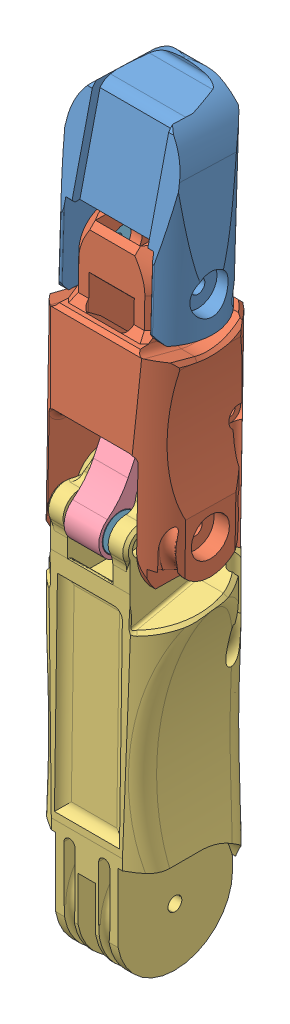
SolidWorks assembly assembly little finger, configuration Default. Lengths in mm.
Overall size (25.08 108.84 19.95).
12 component instances, 5 part files, 24 mates.
Components (placement in the parent):
- little link1-1: little link1 [Default] at (0 -2.2394 -28.6211) x (1 0 0) z (0 0.031595 0.999501) size (19.5 27.22 13.31)
- little link2-1: little link2 [Default] at (0 -32.0849 -28.1064) x (1 0 0) z (0 0.017244 0.999851) size (22.25 39.85 15.23)
- little link3-1: little link3 [Default] at (0 -80.3849 -28.1064) size (25.08 61.6 19.95)
- little linkage-1: little linkage [Default] at (0 -20.132 -28.2916) x (1 0 0) z (0 0.999881 -0.015436) size (5 17.7 32.8)
- bearing 1.5-4-5-2-3: bearing 1.5-4-5-2 [Default] at (0.5 -32.0849 -22.2364) x (0 -0.277062 0.960852) z (0 0.960852 0.277062) size (5 2 5)
- bearing 1.5-4-5-2-4: bearing 1.5-4-5-2 [Default] at (4.35 -32.0849 -28.1064) x (0 -0.277062 0.960852) z (0 0.960852 0.277062) size (5 2 5)
- bearing 1.5-4-5-2-5: bearing 1.5-4-5-2 [Default] at (-0.5 -32.0849 -22.2364) x (0 0.999513 -0.031205) z (0 0.031205 0.999513) size (5 2 5)
- bearing 1.5-4-5-2-6: bearing 1.5-4-5-2 [Default] at (-4.35 -32.0849 -28.1064) x (0 0.885559 0.464527) z (0 -0.464527 0.885559) size (5 2 5)
- bearing 1.5-4-5-2-9: bearing 1.5-4-5-2 [Default] at (-0.5 -5.6656 -34.1448) x (0 0.885559 0.464527) z (0 -0.464527 0.885559) size (5 2 5)
- bearing 1.5-4-5-2-10: bearing 1.5-4-5-2 [Default] at (0.5 -5.6656 -34.1448) x (0 -0.277062 0.960852) z (0 0.960852 0.277062) size (5 2 5)
- bearing 1.5-4-5-2-11: bearing 1.5-4-5-2 [Default] at (-4.35 -2.2394 -28.6211) x (0 0.97481 -0.223037) z (0 0.223037 0.97481) size (5 2 5)
- bearing 1.5-4-5-2-12: bearing 1.5-4-5-2 [Default] at (4.35 -2.2394 -28.6211) x (0 -0.290484 -0.95688) z (0 -0.95688 0.290484) size (5 2 5)
Mates (geometry in assembly coordinates):
- Coincident1: coincident: plane of assembly through (0 0 0) normal (1 0 0); plane of little link3-1 through (0 -80.3849 -28.1064) normal (1 0 0); plane of assembly
- Concentric1: concentric: cylinder of assembly; cylinder of assembly; cylinder of little link2-1 through (7.4 -32.0849 -28.1064) axis (1 0 0) radius 2.75; cylinder of little link3-1 through (-10.4 -32.0849 -28.1064) axis (1 0 0) radius 2.55
- Width1: width: plane of assembly; plane of assembly; plane of assembly; plane of assembly; plane of little link2-1 through (-6.4 -20.1919 -34.4124) normal (1 0 0); plane of little link2-1 through (6.4 -20.1919 -34.4124) normal (-1 0 0); plane of little link3-1 through (5.75 -37.3849 -28.1064) normal (1 0 0); plane of little link3-1 through (-5.75 -37.3849 -28.1064) normal (-1 0 0)
- Concentric2: concentric: cylinder of assembly; cylinder of assembly; cylinder of little link1-1 through (-10.0932 -2.2394 -28.6211) axis (1 0 0) radius 1; cylinder of little link2-1 through (-10.4 -2.2394 -28.6211) axis (1 0 0) radius 2.55
- Width2: width: plane of assembly; plane of assembly; plane of assembly; plane of assembly; plane of little link1-1 through (-6.4 26.6712 -29.535) normal (1 0 0); plane of little link1-1 through (6.4 26.6712 -29.535) normal (-1 0 0); plane of little link2-1 through (-5.75 -7.5386 -28.5297) normal (-1 0 0); plane of little link2-1 through (5.75 -7.5386 -28.5297) normal (1 0 0)
- Concentric3: concentric: cylinder of assembly; cylinder of assembly; cylinder of little link3-1 through (-10.8126 -32.0849 -22.2364) axis (1 0 0) radius 0.65; cylinder of little linkage-1 through (2.5 -32.0849 -22.2364) axis (-1 0 0) radius 2.075
- Concentric5: concentric: cylinder of assembly; cylinder of assembly; cylinder of little link1-1 through (-10.0465 -5.6656 -34.1448) axis (1 0 0) radius 0.7; cylinder of little linkage-1 through (2.5 -5.6656 -34.1448) axis (-1 0 0) radius 2.075
- Width3: width: plane of assembly; plane of assembly; plane of assembly; plane of assembly; plane of little link2-1 through (-3.25 -37.1894 -34.1192) normal (1 0 0); plane of little link2-1 through (3.25 -37.1894 -34.1192) normal (-1 0 0); plane of little linkage-1 through (2.5 -20.132 -28.2916) normal (1 0 0); plane of little linkage-1 through (-2.5 -20.132 -28.2916) normal (-1 0 0)
- Concentric9: concentric: cylinder of assembly; cylinder of assembly; cylinder of little link3-1 through (-10.4 -32.0849 -28.1064) axis (1 0 0) radius 2.55; cylinder of bearing 1.5-4-5-2-4 through (6.35 -32.0849 -28.1064) axis (-1 0 0) radius 2
- Coincident4: coincident: plane of assembly; plane of assembly; plane of little link3-1 through (5.75 -37.3849 -28.1064) normal (1 0 0); plane of bearing 1.5-4-5-2-4 through (5.75 -32.0849 -28.1064) normal (-1 0 0)
- Concentric10: concentric: cylinder of assembly; cylinder of assembly; cylinder of little link3-1 through (-10.8126 -32.0849 -22.2364) axis (1 0 0) radius 0.65; cylinder of bearing 1.5-4-5-2-3 through (2.5 -32.0849 -22.2364) axis (-1 0 0) radius 2
- Coincident5: coincident: plane of assembly; plane of assembly; plane of little linkage-1 through (1.9 -32.0849 -22.2364) normal (1 0 0); plane of bearing 1.5-4-5-2-3 through (1.9 -32.0849 -22.2364) normal (-1 0 0)
- Concentric11: concentric: cylinder of assembly; cylinder of assembly; cylinder of little link3-1 through (-10.4 -32.0849 -28.1064) axis (1 0 0) radius 2.55; cylinder of bearing 1.5-4-5-2-6 through (-6.35 -32.0849 -28.1064) axis (1 0 0) radius 2
- Coincident6: coincident: plane of assembly; plane of assembly; plane of little link3-1 through (-5.75 -37.3849 -28.1064) normal (-1 0 0); plane of bearing 1.5-4-5-2-6 through (-5.75 -32.0849 -28.1064) normal (1 0 0)
- Concentric12: concentric: cylinder of assembly; cylinder of assembly; cylinder of little link3-1 through (-10.8126 -32.0849 -22.2364) axis (1 0 0) radius 0.65; cylinder of bearing 1.5-4-5-2-5 through (-2.5 -32.0849 -22.2364) axis (1 0 0) radius 2
- Concentric15: concentric: cylinder of assembly; cylinder of assembly; cylinder of little linkage-1 through (2.5 -5.6656 -34.1448) axis (-1 0 0) radius 2.075; cylinder of bearing 1.5-4-5-2-9 through (-2.5 -5.6656 -34.1448) axis (1 0 0) radius 2
- Coincident10: coincident: plane of assembly; plane of assembly; plane of little linkage-1 through (-1.9 -5.6656 -34.1448) normal (-1 0 0); plane of bearing 1.5-4-5-2-9 through (-1.9 -5.6656 -34.1448) normal (1 0 0)
- Concentric16: concentric: cylinder of assembly; cylinder of assembly; cylinder of little linkage-1 through (2.5 -5.6656 -34.1448) axis (-1 0 0) radius 2.075; cylinder of bearing 1.5-4-5-2-10 through (2.5 -5.6656 -34.1448) axis (-1 0 0) radius 2
- Coincident11: coincident: plane of assembly; plane of assembly; plane of little linkage-1 through (1.9 -5.6656 -34.1448) normal (1 0 0); plane of bearing 1.5-4-5-2-10 through (1.9 -5.6656 -34.1448) normal (-1 0 0)
- Concentric17: concentric: cylinder of assembly; cylinder of assembly; cylinder of little link2-1 through (-10.4 -2.2394 -28.6211) axis (1 0 0) radius 2.55; cylinder of bearing 1.5-4-5-2-12 through (6.35 -2.2394 -28.6211) axis (-1 0 0) radius 2
- Coincident12: coincident: plane of assembly; plane of assembly; plane of little link2-1 through (5.75 -7.5386 -28.5297) normal (1 0 0); plane of bearing 1.5-4-5-2-12 through (5.75 -2.2394 -28.6211) normal (-1 0 0)
- Concentric18: concentric: cylinder of assembly; cylinder of assembly; cylinder of little link2-1 through (-10.4 -2.2394 -28.6211) axis (1 0 0) radius 2.55; cylinder of bearing 1.5-4-5-2-11 through (-6.35 -2.2394 -28.6211) axis (1 0 0) radius 2
- Coincident13: coincident: plane of assembly; plane of assembly; plane of little link2-1 through (-5.75 -7.5386 -28.5297) normal (-1 0 0); plane of bearing 1.5-4-5-2-11 through (-5.75 -2.2394 -28.6211) normal (1 0 0)
- Coincident14: coincident: plane of assembly; plane of assembly; plane of little linkage-1 through (-1.9 -32.0849 -22.2364) normal (-1 0 0); plane of bearing 1.5-4-5-2-5 through (-1.9 -32.0849 -22.2364) normal (1 0 0)
